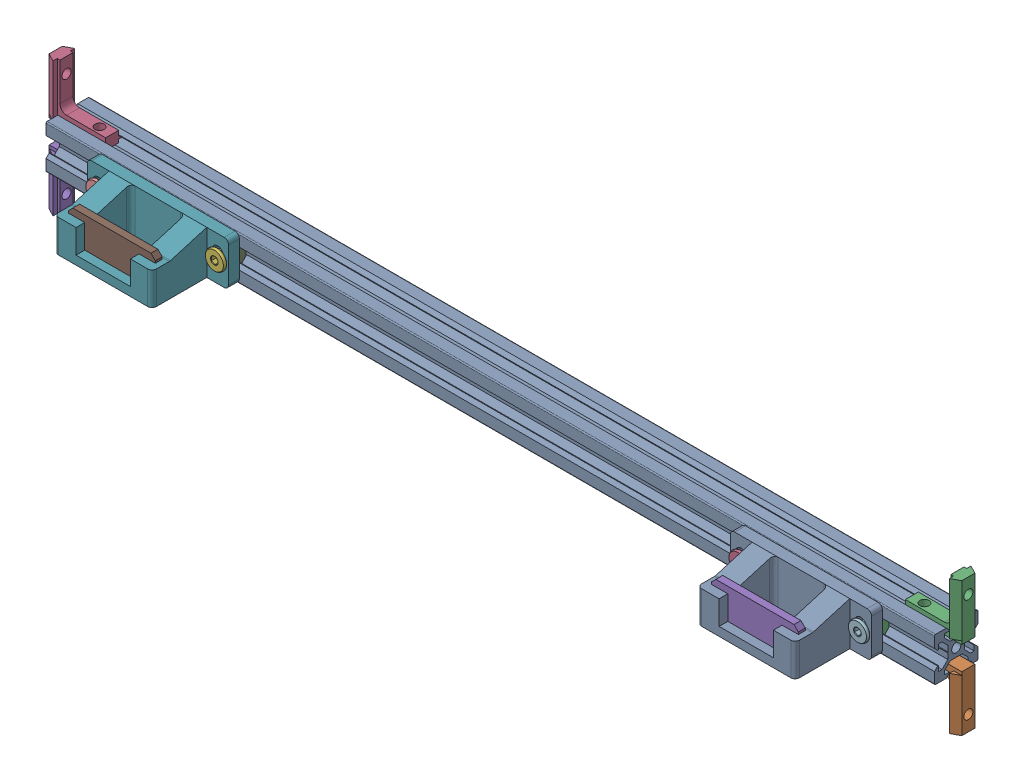
SolidWorks assembly ooze_control_assembly, configuration Default. Lengths in mm.
Overall size (420.1 61.8 50.18).
19 component instances, 6 part files, 0 mates.
Components (placement in the parent):
- 409mm_2020_tslot_extrusion-1: 409mm_2020_tslot_extrusion [Default] at (-419 10 -484.3927) x (1 0 0) z (0 0 -1) size (409 20 20)
- inside_hidden_corner_bracket-1: inside_hidden_corner_bracket [Default] at (5.55 4.6 59.6073) x (0 -1 0) z (0 0 -1) size (25.5 26 10.4)
- inside_hidden_corner_bracket-2: inside_hidden_corner_bracket [Default] at (5.55 15.4 59.6073) x (0 1 0) z (0 0 1) size (25.5 26 10.4)
- inside_hidden_corner_bracket-3: inside_hidden_corner_bracket [Default] at (-414.55 15.4 59.6073) x (0 1 0) z (0 0 -1) size (25.5 26 10.4)
- inside_hidden_corner_bracket-4: inside_hidden_corner_bracket [Default] at (-414.55 4.6 59.6073) x (0 -1 0) z (0 0 1) size (25.5 26 10.4)
- extruder_wiper_assembly-1: extruder_wiper_assembly [Default] at (-257.982 0 99.7823) size (65 20 35.18)
  - m5_low_profile_screw_template_M5 x 10-1: m5_low_profile_screw_template_M5 x 10 [Default] at (-67.018 10 -35.175) x (0 0 -1) z (1 0 0) size (11.62 9 9)
  - ooze_wiper_v1-1: ooze_wiper_v1 [Default] at (-107.018 0 -30.175) size (65 20 30.18)
  - m5_locking_t_nut_20x20_generic-1: m5_locking_t_nut_20x20_generic [Default] at (-119.018 10 -35.175) x (0 -1 0) z (-1 0 0) size (10 4.5 6)
  - m5_locking_t_nut_20x20_generic-2: m5_locking_t_nut_20x20_generic [Default] at (-64.018 10 -35.175) x (0 -1 0) z (-1 0 0) size (10 4.5 6)
  - m5_low_profile_screw_template_M5 x 10-2: m5_low_profile_screw_template_M5 x 10 [Default] at (-122.018 10 -35.175) x (0 0 -1) z (1 0 0) size (11.62 9 9)
  - silicone_wiper-1: silicone_wiper [Default] at (-114.518 3 -7.175) x (1 0 0) z (0 -1 0) size (40 3.17 15)
- extruder_wiper_assembly_2-1: extruder_wiper_assembly_2 [Default] at (38.018 0 99.7823) size (65 20 35.18)
  - m5_low_profile_screw_template_M5 x 10-1: m5_low_profile_screw_template_M5 x 10 [Default] at (-67.018 10 -35.175) x (0 0 -1) z (1 0 0) size (11.62 9 9)
  - ooze_wiper_v1-1: ooze_wiper_v1 [Default] at (-107.018 0 -30.175) size (65 20 30.18)
  - m5_locking_t_nut_20x20_generic-1: m5_locking_t_nut_20x20_generic [Default] at (-119.018 10 -35.175) x (0 -1 0) z (-1 0 0) size (10 4.5 6)
  - m5_locking_t_nut_20x20_generic-2: m5_locking_t_nut_20x20_generic [Default] at (-64.018 10 -35.175) x (0 -1 0) z (-1 0 0) size (10 4.5 6)
  - m5_low_profile_screw_template_M5 x 10-2: m5_low_profile_screw_template_M5 x 10 [Default] at (-122.018 10 -35.175) x (0 0 -1) z (1 0 0) size (11.62 9 9)
  - silicone_wiper-1: silicone_wiper [Default] at (-114.518 3 -7.175) x (1 0 0) z (0 -1 0) size (40 3.17 15)
